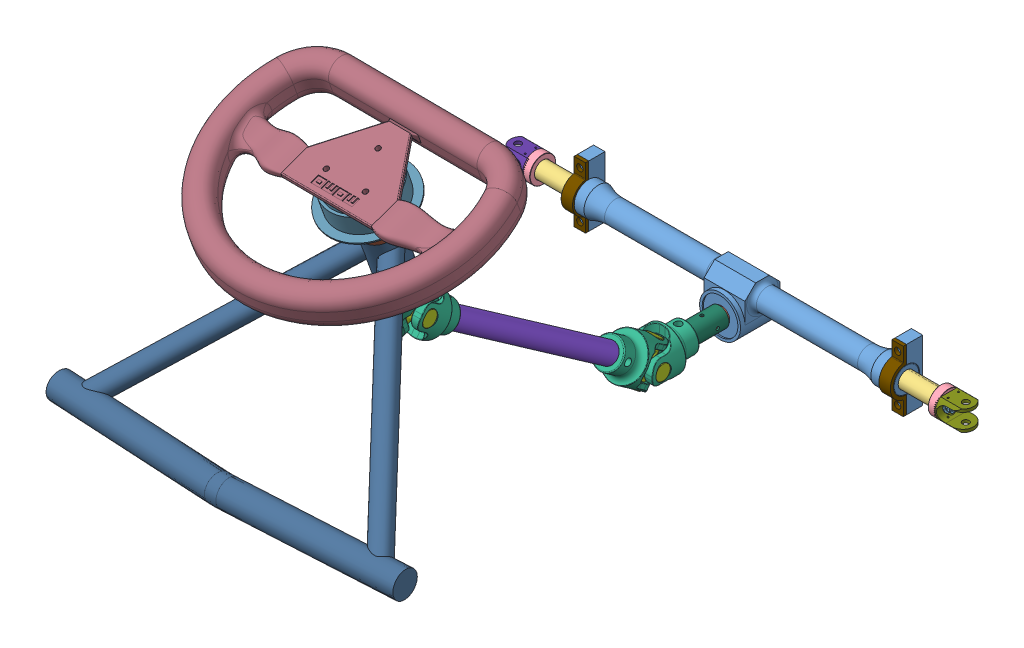
SolidWorks assembly ST-A0200-AA-Inboard Steering, configuration Default. Lengths in mm.
Overall size (453.39 406.81 546.68).
33 component instances, 20 part files, 50 mates.
Components (placement in the parent):
- ST-00020-AA-NARRco Rack MkII-1: ST-00020-AA-NARRco Rack MkII [13t-Custom Length] at (0 -158.974 -60.8538) x (0 0 1) z (0 -1 0) size (60.02 415.44 50.74)
  - ST-00020-AA-NARRco Rack MkII Housing^ST-00020-AA-NARRco Rack MkII-2: ST-00020-AA-NARRco Rack MkII Housing^ST-00020-AA-NARRco Rack MkII [17.4] at origin size (38.43 322.07 50.74) (virtual)
  - ST-00021-AA-NARRco Rack MkII Pinion^ST-00020-AA-NARRco Rack MkII-1: ST-00021-AA-NARRco Rack MkII Pinion^ST-00020-AA-NARRco Rack MkII [Default] at (0 0 16.002) x (1 0 0) z (0 -1 0) size (58.42 31.97 31.97) (virtual)
  - ST-00022-AA-NARRco Rack MkII Rack^ST-00020-AA-NARRco Rack MkII-1: ST-00022-AA-NARRco Rack MkII Rack^ST-00020-AA-NARRco Rack MkII [17.4] at origin size (15.88 404.88 15.88) (virtual)
  - ST-00023-AA-NARRco Rack MkII Bump Stop TT1119-01^ST-00020-AA-NARRco Rack MkII-1: ST-00023-AA-NARRco Rack MkII Bump Stop TT1119-01^ST-00020-AA-NARRco Rack MkII [Default] at (0 194.818 0) x (-1 0 0) z (0 1 0) size (25.4 25.4 7.62) (virtual)
  - ST-00023-AA-NARRco Rack MkII Bump Stop TT1119-01^ST-00020-AA-NARRco Rack MkII-2: ST-00023-AA-NARRco Rack MkII Bump Stop TT1119-01^ST-00020-AA-NARRco Rack MkII [Default] at (0 -194.818 0) x (1 0 0) z (0 -1 0) size (25.4 25.4 7.62) (virtual)
  - ST-10024-AA-Rack End Fastener^ST-00020-AA-NARRco Rack MkII-1: ST-10024-AA-Rack End Fastener^ST-00020-AA-NARRco Rack MkII [Default] at (0 202.438 0) x (-0.837169 0 -0.546944) z (0 -1 0) size (12.7 12.7 31.32) (virtual)
  - ST-10024-AA-Rack End Fastener^ST-00020-AA-NARRco Rack MkII-2: ST-10024-AA-Rack End Fastener^ST-00020-AA-NARRco Rack MkII [Default] at (0 -202.438 0) x (-0.837169 0 -0.546944) z (0 1 0) size (12.7 12.7 31.32) (virtual)
- ST-00007-AA-SU Joint Borgeson-1: ST-00007-AA-SU Joint Borgeson [Default] at (0 -174.976 36.3378) x (0 0.573576 0.819152) z (-1 0 0) size (87.37 64.05 41.39)
  - Clevis^ST-00007-AA-SU Joint Borgeson-1: Clevis^ST-00007-AA-SU Joint Borgeson [Default] at (19.25 0 0) size (52.55 41.35 41.39) (virtual)
  - Clevis^ST-00007-AA-SU Joint Borgeson-2: Clevis^ST-00007-AA-SU Joint Borgeson [Default] at (-15.7687 11.0413 0) x (-0.819152 0.573576 0) z (0.573576 0.819152 0) size (52.55 41.35 41.39) (virtual)
  - Joint^ST-00007-AA-SU Joint Borgeson-1: Joint^ST-00007-AA-SU Joint Borgeson [Default] at origin size (15.41 40.1 40.1) (virtual)
- ST-10008-AG-Lower Column-1: ST-10008-AG-Lower Column [Single U-Joint] at (0 -176.646 33.9528) x (-0.165712 -0.807827 0.565646) z (0 0.573576 0.819152) size (30.03 24.96 239.93)
- ST-00007-AB-SU Joint Borgeson-1: ST-00007-AB-SU Joint Borgeson [Default] at (272.5838 -275.7567 2.1298) x (0 0.984808 -0.173648) z (0 0.173648 0.984808) size (106.79 41.39 97.86)
  - ST-00007-AA-SU Joint Borgeson-1: ST-00007-AA-SU Joint Borgeson [Default] at (210.9791 272.5838 303.532) x (0.866025 0 0.5) z (0 1 0) size (87.37 64.05 41.39)
    - Clevis^ST-00007-AA-SU Joint Borgeson-1: Clevis^ST-00007-AA-SU Joint Borgeson [Default] at (19.25 0 0) size (52.55 41.35 41.39) (virtual)
    - Clevis^ST-00007-AA-SU Joint Borgeson-2: Clevis^ST-00007-AA-SU Joint Borgeson [Default] at (-15.7687 11.0413 0) x (-0.819152 0.573576 0) z (0.573576 0.819152 0) size (52.55 41.35 41.39) (virtual)
    - Joint^ST-00007-AA-SU Joint Borgeson-1: Joint^ST-00007-AA-SU Joint Borgeson [Default] at origin size (15.41 40.1 40.1) (virtual)
- ST-10004-AC-Upper Column-1: ST-10004-AC-Upper Column [Default] at (0 -15.2751 264.4144) x (0 0.939693 0.34202) z (-0.909534 0.142154 -0.390564) size (101.6 19.05 19.05)
- ST-10005-BB-Upper Support-4: ST-10005-BB-Upper Support [Default] at (0 47.65 287.3172) x (-1 0 0) z (0 1 0) size (339.46 194.46 164.58)
- ST-00006-AA-Upper Column Bearing (2938T23)-1: ST-00006-AA-Upper Column Bearing (2938T23) [Default] at (0 23.7222 278.6082) x (0 0.939693 0.34202) z (-0.975708 -0.074928 0.205863) size (19.05 31.75 31.75)
- ST-00006-AA-Upper Column Bearing (2938T23)-2: ST-00006-AA-Upper Column Bearing (2938T23) [Default] at (0 71.5779 296.0263) x (0 -0.939693 -0.34202) z (0.727107 -0.234805 0.645121) size (19.05 31.75 31.75)
- ST-00003-AA-Longacre Spud-1: ST-00003-AA-Longacre Spud [Default] at (0 93.9543 304.1706) x (0 -0.939693 -0.34202) z (0.869392 -0.169 0.464323) size (53.97 27.38 27.32)
- ST-#####-AA-MOMO MOD 12-1: ST-#####-AA-MOMO MOD 12 [Default] at (0 119.9927 313.6478) x (-0.999984 0.001925 -0.00529) z (0 0.939693 0.34202) size (250 198.03 35.56)
- ST-00002-AA-Longacre Quick Disconnect_52-56605-1: ST-00002-AA-Longacre Quick Disconnect_52-56605 [Default] at (0 102.9646 307.4501) x (0 -0.939693 -0.34202) z (0.868826 0.16934 -0.465258) size (41.4 80.01 80.01)
- ST-10009-AA-Lower Lower Column-1: ST-10009-AA-Lower Lower Column [Single U-Joint] at (0 -174.976 -60.8538) x (0 1 0) z (0 0 1) size (30.03 24.96 55.78)
- ST-10025-AA-Rack End Left-1: ST-10025-AA-Rack End Left [Brute Forced Left] at (211.328 -158.974 -60.8538) x (0 0 -1) z (0 -1 0) size (25.4 30.73 21.27)
- ST-10025-AA-Rack End-1: ST-10025-AA-Rack End [Right] at (-211.328 -158.974 -60.8538) x (0 0 1) z (0 -1 0) size (25.4 30.73 21.27)
- ST-00011-AB-Rack Mount Top-1: ST-00011-AB-Rack Mount Top [Default] at (-155.4861 -158.974 -60.8538) x (0 1 0) z (0 0 1) size (59.69 11.13 15.88)
- ST-00011-AB-Rack Mount Top-2: ST-00011-AB-Rack Mount Top [Default] at (155.4861 -158.974 -60.8538) x (0 1 0) z (0 0 1) size (59.69 11.13 15.88)
- ST-00012-AB-Rack Mount Bottom-1: ST-00012-AB-Rack Mount Bottom [Default] at (-155.4861 -158.974 -60.8538) x (0 1 0) z (0 0 1) size (59.69 11.13 15.88)
- ST-00012-AB-Rack Mount Bottom-2: ST-00012-AB-Rack Mount Bottom [Default] at (155.4861 -158.974 -60.8538) x (0 1 0) z (0 0 1) size (59.69 11.13 15.88)
- ST-70001-AB-Steering Rack Cover-1: ST-70001-AB-Steering Rack Cover [Default] at (161.925 -244.8955 -31.75) x (-1 0 0) z (0 0 -1) size (388.4 152.4 55.88)
Mates (geometry in assembly coordinates):
- Angle2: planar angle = 0 rad anti-aligned: plane of ST-00020-AA-NARRco Rack MkII-1/ST-00020-AA-NARRco Rack MkII Housing^ST-00020-AA-NARRco Rack MkII-2 through (0 -158.974 -77.8718) normal (0 0 -1)
- Parallel1: parallel aligned: plane of ST-00020-AA-NARRco Rack MkII-1/ST-00020-AA-NARRco Rack MkII Housing^ST-00020-AA-NARRco Rack MkII-2 through (-20.0025 -158.974 -43.8358) normal (-1 0 0); plane of ST-00007-AA-SU Joint Borgeson-1/Clevis^ST-00007-AA-SU Joint Borgeson-1 through (-11.125 -180.8297 63.9365) normal (-1 0 0)
- Coincident33: coincident aligned: plane of ST-00007-AA-SU Joint Borgeson-1/Clevis^ST-00007-AA-SU Joint Borgeson-1 through (11.125 -180.8297 63.9365) normal (1 0 0); plane of ST-00007-AB-SU Joint Borgeson-1/ST-00007-AA-SU Joint Borgeson-1/Clevis^ST-00007-AA-SU Joint Borgeson-1 through (11.125 -4.2402 290.3794) normal (1 0 0)
- Concentric2: concentric aligned: cylinder of ST-00007-AA-SU Joint Borgeson-1/Clevis^ST-00007-AA-SU Joint Borgeson-1 through (0 -176.414 34.2842) axis (0 -0.573576 -0.819152) radius 9.525; cylinder of ST-10008-AG-Lower Column-1 through (0 -176.646 33.9528) axis (0 -0.573576 -0.819152) radius 9.525
- Coincident4: coincident aligned: plane of ST-00007-AA-SU Joint Borgeson-1/Clevis^ST-00007-AA-SU Joint Borgeson-1 through (12.7 -163.9347 52.1065) normal (0 -0.573576 -0.819152); plane of ST-10008-AG-Lower Column-1 through (-1.3153 -170.3468 56.5963) normal (0 -0.573576 -0.819152)
- Concentric4: concentric anti-aligned: cylinder of ST-10008-AG-Lower Column-1 through (0 -176.646 33.9528) axis (0 -0.573576 -0.819152) radius 9.525; cylinder of ST-00007-AB-SU Joint Borgeson-1/ST-00007-AA-SU Joint Borgeson-1/Clevis^ST-00007-AA-SU Joint Borgeson-2 through (0 -13.8371 266.468) axis (0 0.573576 0.819152) radius 9.525
- Coincident5: coincident aligned: plane of ST-10008-AG-Lower Column-1 through (-1.5784 -34.011 254.0335) normal (0 0.573576 0.819152); plane of ST-00007-AB-SU Joint Borgeson-1/ST-00007-AA-SU Joint Borgeson-1/Clevis^ST-00007-AA-SU Joint Borgeson-2 through (0 -36.7196 255.9301) normal (0 0.573576 0.819152)
- Concentric5: concentric anti-aligned: cylinder of ST-00007-AB-SU Joint Borgeson-1/ST-00007-AA-SU Joint Borgeson-1/Clevis^ST-00007-AA-SU Joint Borgeson-1 through (0 -17.6309 263.5569) axis (0 -0.939693 -0.34202) radius 9.525; cylinder of ST-10004-AC-Upper Column-1 through (0 132.5611 318.2224) axis (0 0.939693 0.34202) radius 9.525
- Coincident6: coincident aligned: plane of ST-00007-AB-SU Joint Borgeson-1/ST-00007-AA-SU Joint Borgeson-1/Clevis^ST-00007-AA-SU Joint Borgeson-1 through (12.7 2.814 270.9983) normal (0 -0.939693 -0.34202); plane of ST-10004-AC-Upper Column-1 through (7.2194 1.6857 274.0984) normal (0 -0.939693 -0.34202)
- Concentric6: concentric anti-aligned: cylinder of ST-10004-AC-Upper Column-1 through (0 132.5611 318.2224) axis (0 0.939693 0.34202) radius 9.525; cylinder of ST-10005-BB-Upper Support-4 through (0 119.9734 313.6408) axis (0 -0.939693 -0.34202) radius 12.7
- Concentric7: concentric anti-aligned: cylinder of ST-10004-AC-Upper Column-1 through (0 132.5611 318.2224) axis (0 0.939693 0.34202) radius 9.525; cylinder of ST-00006-AA-Upper Column Bearing (2938T23)-1 through (0 28.1975 280.2371) axis (0 -0.939693 -0.34202) radius 9.5377
- Coincident7: coincident anti-aligned: plane of ST-00007-AB-SU Joint Borgeson-1/ST-00007-AA-SU Joint Borgeson-1/Clevis^ST-00007-AA-SU Joint Borgeson-1 through (9.525 23.7222 278.6082) normal (0 0.939693 0.34202); plane of ST-00006-AA-Upper Column Bearing (2938T23)-1 through (0 23.7222 278.6082) normal (0 -0.939693 -0.34202)
- Coincident8: coincident anti-aligned: plane of ST-10005-BB-Upper Support-4 through (0 28.1975 280.2371) normal (0 -0.939693 -0.34202); plane of ST-00006-AA-Upper Column Bearing (2938T23)-1 through (0 28.1975 280.2371) normal (0 0.939693 0.34202)
- Concentric8: concentric aligned: cylinder of ST-10004-AC-Upper Column-1 through (0 132.5611 318.2224) axis (0 0.939693 0.34202) radius 9.525; cylinder of ST-00006-AA-Upper Column Bearing (2938T23)-2 through (0 67.1026 294.3974) axis (0 0.939693 0.34202) radius 9.5377
- Coincident9: coincident anti-aligned: plane of ST-10005-BB-Upper Support-4 through (0 67.1026 294.3974) normal (0 0.939693 0.34202); plane of ST-00006-AA-Upper Column Bearing (2938T23)-2 through (0 67.1026 294.3974) normal (0 -0.939693 -0.34202)
- Concentric9: concentric aligned: cylinder of ST-10004-AC-Upper Column-1 through (0 132.5611 318.2224) axis (0 0.939693 0.34202) radius 9.525; cylinder of ST-00003-AA-Longacre Spud-1 through (0 133.484 318.5582) axis (0 0.939693 0.34202) radius 9.525
- Coincident10: coincident anti-aligned: plane of ST-00006-AA-Upper Column Bearing (2938T23)-2 through (0 71.5779 296.0263) normal (0 0.939693 0.34202); plane of ST-00003-AA-Longacre Spud-1 through (8.281 69.9682 300.4489) normal (0 -0.939693 -0.34202)
- Concentric11: concentric anti-aligned: cylinder of ST-00003-AA-Longacre Spud-1 through (0 133.484 318.5582) axis (0 0.939693 0.34202) radius 11.811; cylinder of ST-00002-AA-Longacre Quick Disconnect_52-56605-1 through (0 131.3998 317.7997) axis (0 -0.939693 -0.34202) radius 14.605
- Parallel4: parallel anti-aligned: plane of ST-00003-AA-Longacre Spud-1 through (4.8313 73.8291 289.8411) normal (0.591719 0.275717 -0.757528); plane of ST-00002-AA-Longacre Quick Disconnect_52-56605-1 through (9.5444 94.0384 299.6695) normal (-0.591719 -0.275717 0.757528)
- Coincident12: coincident aligned: plane of ST-00003-AA-Longacre Spud-1 through (10.2684 81.5159 305.854) normal (0 -0.939693 -0.34202); plane of ST-00002-AA-Longacre Quick Disconnect_52-56605-1 through (20.4131 87.4906 289.4387) normal (0 -0.939693 -0.34202)
- Coincident13: coincident anti-aligned: plane of ST-#####-AA-MOMO MOD 12-1 through (44.6995 137.5341 272.9967) normal (0 -0.939693 -0.34202); plane of ST-00002-AA-Longacre Quick Disconnect_52-56605-1 through (11.0341 124.5678 308.6215) normal (0 0.939693 0.34202)
- Concentric12: concentric aligned: cylinder of ST-#####-AA-MOMO MOD 12-1 through (19.1846 118.5795 325.0742) axis (0 0.939693 0.34202) radius 2.413; cylinder of ST-00002-AA-Longacre Quick Disconnect_52-56605-1 through (19.1846 112.6124 322.9024) axis (0 0.939693 0.34202) radius 3.9688
- Concentric13: concentric aligned: cylinder of ST-#####-AA-MOMO MOD 12-1 through (-19.3097 118.6536 324.8706) axis (0 0.939693 0.34202) radius 2.413; cylinder of ST-00002-AA-Longacre Quick Disconnect_52-56605-1 through (-19.3097 112.6865 322.6988) axis (0 0.939693 0.34202) radius 3.9688
- Concentric14: concentric anti-aligned: cylinder of ST-00020-AA-NARRco Rack MkII-1/ST-00021-AA-NARRco Rack MkII Pinion^ST-00020-AA-NARRco Rack MkII-1 through (-15.988 -174.976 -27.6903) axis (1 0 0) radius 1.5875; cylinder of ST-10009-AA-Lower Lower Column-1 through (9.525 -174.976 -27.6903) axis (-1 0 0) radius 1.5875
- Concentric15: concentric anti-aligned: cylinder of ST-00020-AA-NARRco Rack MkII-1/ST-00021-AA-NARRco Rack MkII Pinion^ST-00020-AA-NARRco Rack MkII-1 through (0 -174.976 -29.2778) axis (0 0 1) radius 7.9375; cylinder of ST-10009-AA-Lower Lower Column-1 through (0 -174.976 -60.8538) axis (0 0 -1) radius 7.9375
- Coincident16: coincident aligned: plane of ST-00007-AA-SU Joint Borgeson-1/Clevis^ST-00007-AA-SU Joint Borgeson-2 through (0 -187.676 17.0878) normal (0 0 1); plane of ST-10009-AA-Lower Lower Column-1 through (0 -165.451 17.0878) normal (0 0 1)
- Concentric17: concentric anti-aligned: cylinder of ST-00007-AA-SU Joint Borgeson-1/Clevis^ST-00007-AA-SU Joint Borgeson-2 through (0 -174.976 38.8448) axis (0 0 1) radius 9.525; cylinder of ST-10009-AA-Lower Lower Column-1 through (0 -174.976 -60.8538) axis (0 0 -1) radius 9.525
- Concentric19: concentric anti-aligned: cylinder of ST-00020-AA-NARRco Rack MkII-1/ST-10024-AA-Rack End Fastener^ST-00020-AA-NARRco Rack MkII-2 through (207.7212 -158.974 -60.8538) axis (1 0 0) radius 6.35; cylinder of ST-10025-AA-Rack End Left-1 through (226.695 -158.974 -60.8538) axis (-1 0 0) radius 4.7625
- Angle3: planar angle = 0.610865 rad aligned: plane of ST-00020-AA-NARRco Rack MkII-1/ST-00022-AA-NARRco Rack MkII Rack^ST-00020-AA-NARRco Rack MkII-1 through (197.866 -165.324 -65.6163) normal (0 -1 0); plane of ST-10025-AA-Rack End Left-1 through (200.406 -153.7204 -64.5324) normal (0 -0.819152 0.573576)
- Coincident19: coincident aligned: plane of ST-00020-AA-NARRco Rack MkII-1/ST-00022-AA-NARRco Rack MkII Rack^ST-00020-AA-NARRco Rack MkII-1 through (202.438 -158.974 -60.8538) normal (1 0 0); plane of ST-10025-AA-Rack End Left-1 through (202.438 -158.974 -60.8538) normal (1 0 0)
- Concentric20: concentric anti-aligned: cylinder of ST-00020-AA-NARRco Rack MkII-1/ST-10024-AA-Rack End Fastener^ST-00020-AA-NARRco Rack MkII-1 through (-207.7212 -158.974 -60.8538) axis (-1 0 0) radius 6.35; cylinder of ST-10025-AA-Rack End-1 through (-226.695 -158.974 -60.8538) axis (1 0 0) radius 4.7625
- Angle4: planar angle = 0.610865 rad aligned: plane of ST-00020-AA-NARRco Rack MkII-1/ST-00022-AA-NARRco Rack MkII Rack^ST-00020-AA-NARRco Rack MkII-1 through (-197.866 -165.324 -65.6163) normal (0 -1 0); plane of ST-10025-AA-Rack End-1 through (-200.406 -153.7204 -64.5324) normal (0 -0.819152 0.573576)
- Coincident21: coincident aligned: plane of ST-00020-AA-NARRco Rack MkII-1/ST-00022-AA-NARRco Rack MkII Rack^ST-00020-AA-NARRco Rack MkII-1 through (-202.438 -158.974 -60.8538) normal (-1 0 0); plane of ST-10025-AA-Rack End-1 through (-202.438 -158.974 -60.8538) normal (-1 0 0)
- Concentric21: concentric anti-aligned: cylinder of ST-00020-AA-NARRco Rack MkII-1/ST-00020-AA-NARRco Rack MkII Housing^ST-00020-AA-NARRco Rack MkII-2 through (-220.98 -158.974 -60.8538) axis (-1 0 0) radius 12.7; cylinder of ST-00011-AB-Rack Mount Top-1 through (-161.0487 -158.974 -60.8538) axis (1 0 0) radius 12.7
- Coincident22: coincident anti-aligned: plane of ST-00020-AA-NARRco Rack MkII-1/ST-00020-AA-NARRco Rack MkII Housing^ST-00020-AA-NARRco Rack MkII-2 through (-149.9235 -171.674 -60.8538) normal (-1 0 0); plane of ST-00011-AB-Rack Mount Top-1 through (-149.9235 -158.974 -60.8538) normal (1 0 0)
- Concentric22: concentric anti-aligned: cylinder of ST-00020-AA-NARRco Rack MkII-1/ST-00020-AA-NARRco Rack MkII Housing^ST-00020-AA-NARRco Rack MkII-2 through (-220.98 -158.974 -60.8538) axis (-1 0 0) radius 12.7; cylinder of ST-00011-AB-Rack Mount Top-2 through (149.9235 -158.974 -60.8538) axis (1 0 0) radius 12.7
- Coincident23: coincident anti-aligned: plane of ST-00020-AA-NARRco Rack MkII-1/ST-00020-AA-NARRco Rack MkII Housing^ST-00020-AA-NARRco Rack MkII-2 through (149.9235 -171.674 -60.8538) normal (1 0 0); plane of ST-00011-AB-Rack Mount Top-2 through (149.9235 -158.974 -60.8538) normal (-1 0 0)
- Concentric23: concentric anti-aligned: cylinder of ST-00020-AA-NARRco Rack MkII-1/ST-00020-AA-NARRco Rack MkII Housing^ST-00020-AA-NARRco Rack MkII-2 through (-220.98 -158.974 -60.8538) axis (-1 0 0) radius 12.7; cylinder of ST-00012-AB-Rack Mount Bottom-1 through (-161.0487 -158.974 -60.8538) axis (1 0 0) radius 12.7
- Coincident24: coincident aligned: plane of ST-00011-AB-Rack Mount Top-1 through (-161.0487 -158.974 -60.8538) normal (-1 0 0); plane of ST-00012-AB-Rack Mount Bottom-1 through (-161.0487 -158.974 -60.8538) normal (-1 0 0)
- Coincident25: coincident anti-aligned: plane of ST-00011-AB-Rack Mount Top-1 through (-161.0487 -146.274 -60.8538) normal (0 0 -1); plane of ST-00012-AB-Rack Mount Bottom-1 through (-161.0487 -129.129 -60.8538) normal (0 0 1)
- Concentric24: concentric anti-aligned: cylinder of ST-00020-AA-NARRco Rack MkII-1/ST-00020-AA-NARRco Rack MkII Housing^ST-00020-AA-NARRco Rack MkII-2 through (-220.98 -158.974 -60.8538) axis (-1 0 0) radius 12.7; cylinder of ST-00012-AB-Rack Mount Bottom-2 through (149.9235 -158.974 -60.8538) axis (1 0 0) radius 12.7
- Coincident28: coincident anti-aligned: plane of ST-00011-AB-Rack Mount Top-2 through (149.9235 -146.274 -60.8538) normal (0 0 -1); plane of ST-00012-AB-Rack Mount Bottom-2 through (149.9235 -129.129 -60.8538) normal (0 0 1)
- Coincident29: coincident aligned: plane of ST-00011-AB-Rack Mount Top-2 through (149.9235 -158.974 -60.8538) normal (-1 0 0); plane of ST-00012-AB-Rack Mount Bottom-2 through (149.9235 -158.974 -60.8538) normal (-1 0 0)
- Parallel9: parallel anti-aligned: plane of ST-00012-AB-Rack Mount Bottom-1 through (-161.0487 -188.819 -76.7288) normal (0 0 -1)
- Parallel10: parallel anti-aligned: plane of ST-00012-AB-Rack Mount Bottom-2 through (149.9235 -188.819 -76.7288) normal (0 0 -1)
- Coincident31: coincident anti-aligned: plane of ST-00020-AA-NARRco Rack MkII-1 through (0 -158.974 -60.8538) normal (-1 0 0)
- Coincident34: coincident: point of ST-10005-BB-Upper Support-4; plane of assembly
- Distance1: distance = 31.75 mm anti-aligned: plane of ST-70001-AB-Steering Rack Cover-1 through (161.925 -244.8955 -31.75) normal (0 0 -1)
- Distance2: distance = 31.75 mm anti-aligned: plane of ST-70001-AB-Steering Rack Cover-1 through (161.925 -220.569 -58.2235) normal (0 1 0); plane of ST-00012-AB-Rack Mount Bottom-1 through (-161.0487 -188.819 -60.8538) normal (0 -1 0)
- Distance3: distance = 161.925 mm anti-aligned: plane of ST-70001-AB-Steering Rack Cover-1 through (161.925 -244.8955 -31.75) normal (-1 0 0)
